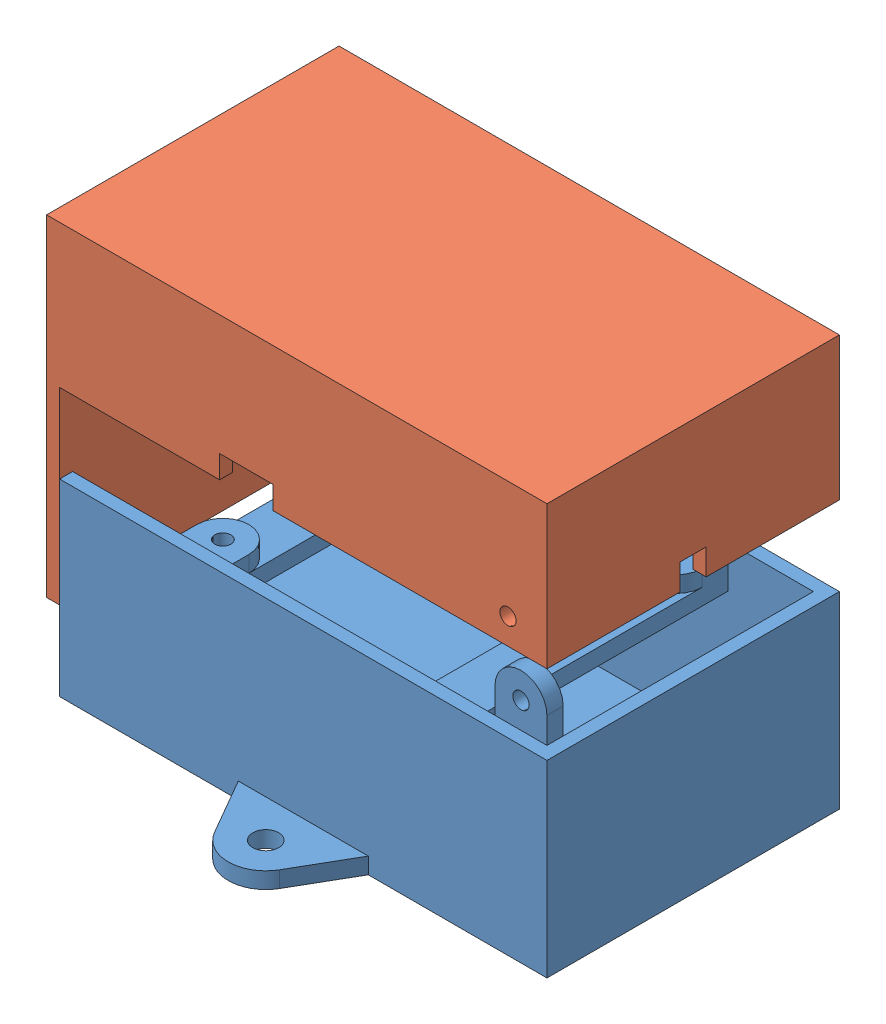
SolidWorks assembly Assem1, configuration Default. Lengths in mm.
Overall size (77 63.21 68.09).
2 component instances, 2 part files, 2 mates.
Components (placement in the parent):
- Karp-1: Karp [Default] at (-18.9644 26.4345 90.9803) size (75 37 68.09)
- Kaas-1: Kaas [Default] at (-19.9644 89.6397 90.9803) x (1 0 0) z (0 0 -1) size (77 51 45)
Mates (geometry in assembly coordinates):
- Coincident9: coincident anti-aligned: plane of Karp-1 through (-56.4644 28.9345 113.4803) normal (-1 0 0); plane of Kaas-1 through (-56.4644 67.6397 70.4803) normal (1 0 0)
- Coincident11: coincident aligned: plane of Karp-1 through (-56.4644 28.9345 113.4803) normal (0 0 1); plane of Kaas-1 through (-58.4644 87.6397 113.4803) normal (0 0 1)
